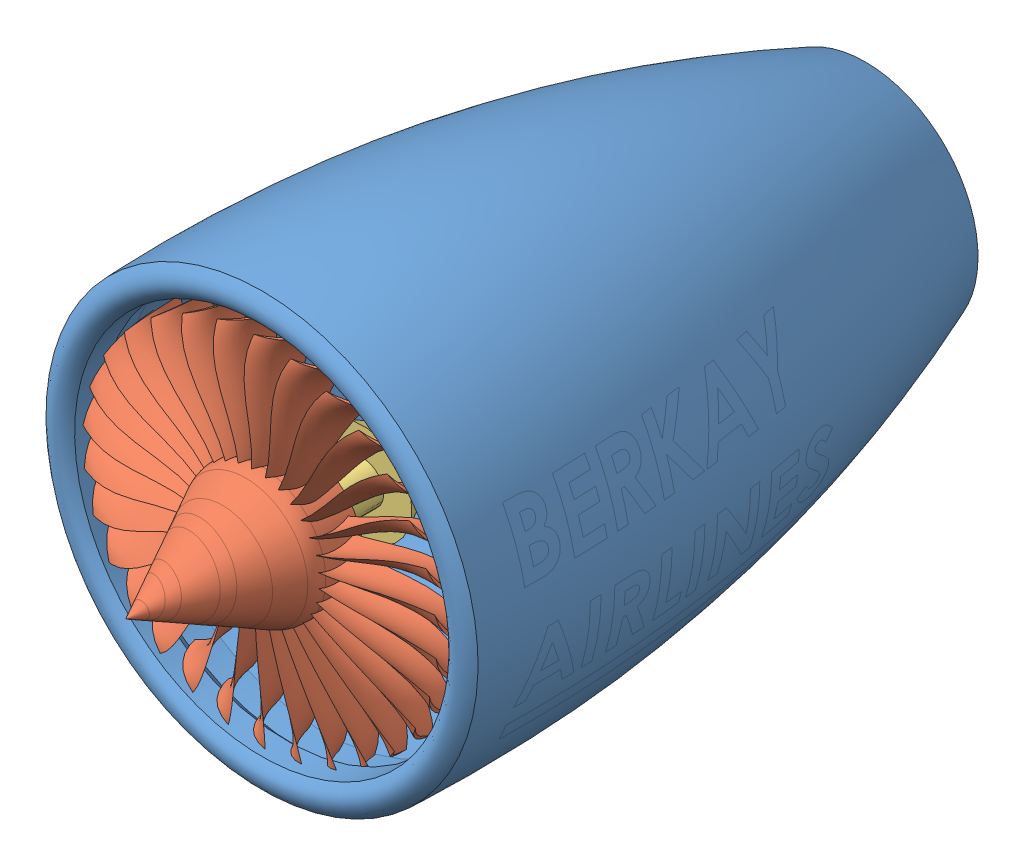
SolidWorks assembly jet-engine-full, configuration Default. Lengths in mm.
Overall size (479.94 480.27 778).
3 component instances, 3 part files, 5 mates.
Components (placement in the parent):
- Part3-1: Part3 [Default] at (1064.029 -553.0724 973.264) x (0 0 -1) z (1 0 0) size (587.71 427.58 427.58)
- Part1-2: Part1 [Default] at (1064.029 -553.0724 1104.264) x (0.827176 -0.561943 0) z (0 0 1) size (345 346.23 169.14)
- Part2-1: Part2 [Default] at (1064.029 -553.0724 976.264) x (0 0 -1) z (0.827176 -0.561943 0) size (650 200.29 200.65)
Mates (geometry in assembly coordinates):
- Concentric1: concentric aligned: cylinder of Part1-2 through (1064.029 -553.0724 976.264) axis (0 0 -1) radius 20; cylinder of Part2-1 through (1064.029 -553.0724 376.264) axis (0 0 -1) radius 20
- Coincident1: coincident anti-aligned: plane of Part1-2 through (1064.029 -553.0724 976.264) normal (0 0 -1); plane of Part2-1 through (1064.029 -553.0724 976.264) normal (0 0 1)
- Concentric5: concentric anti-aligned: cylinder of Part3-1 through (1064.029 -553.0724 297.9583) axis (0 0 1) radius 190; cylinder of Part2-1 through (1064.029 -553.0724 376.264) axis (0 0 -1) radius 40.6822
- Coincident18: coincident anti-aligned: circle of Part3-1; plane of Part1-2 through (1064.029 -553.0724 938.264) normal (0 0 -1)
- Coincident21: coincident aligned: plane of Part1-2 through (1064.029 -553.0724 1104.264) normal (-0.884502 -0.466536 0); plane of Part2-1 through (1064.029 -553.0724 976.264) normal (-0.884502 -0.466536 0)
